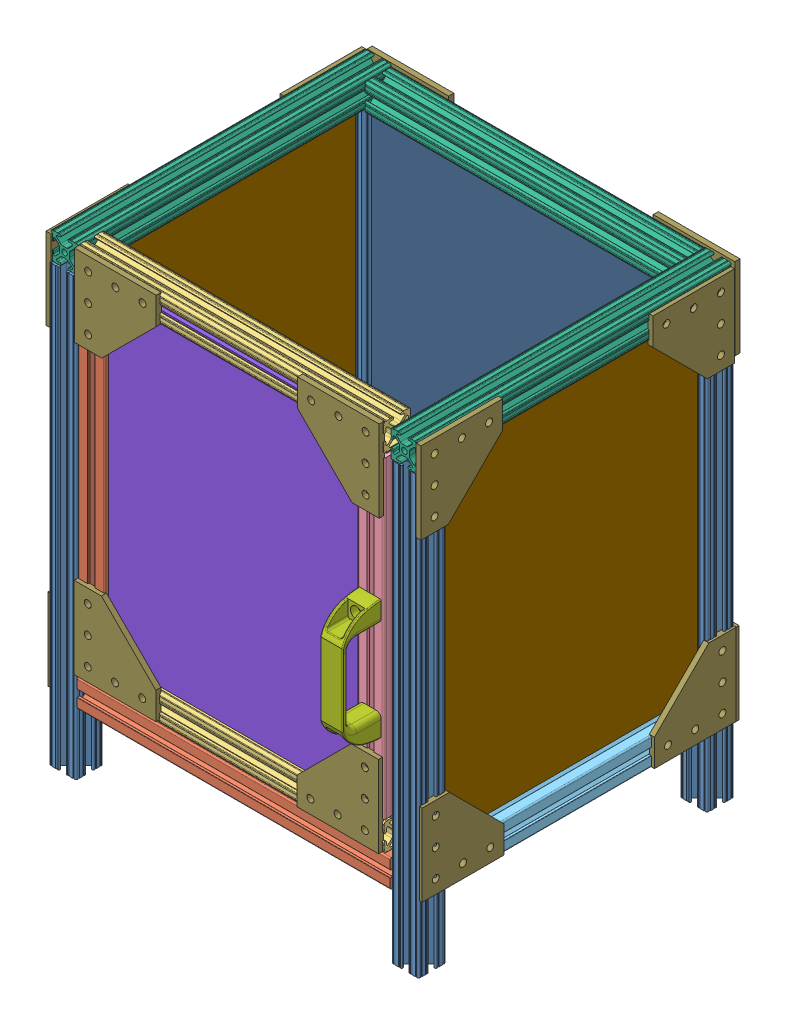
SolidWorks assembly Box_Ext_6_25_2024, configuration Default. Lengths in mm.
Overall size (350.11 433.76 336.93).
41 component instances, 12 part files, 0 mates.
Components (placement in the parent):
- 1A_1D_16in47065T801_T-Slotted Framing rail-1: 1A_1D_16in47065T801_T-Slotted Framing rail [47065T801] at (-239.4342 265.817 193.973) x (0 0 1) z (0 1 0) size (25.4 25.4 406.4)
- 1A_1D_16in47065T801_T-Slotted Framing rail-2: 1A_1D_16in47065T801_T-Slotted Framing rail [47065T801] at (-240.0711 265.9257 462.8579) x (1 0 0) z (0 -1 0) size (25.4 25.4 406.4)
- 1A_1D_16in47065T801_T-Slotted Framing rail-3: 1A_1D_16in47065T801_T-Slotted Framing rail [47065T801] at (79.5241 264.9055 193.6515) x (1 0 0) z (0 -1 0) size (25.4 25.4 406.4)
- 1A_1D_16in47065T801_T-Slotted Framing rail-4: 1A_1D_16in47065T801_T-Slotted Framing rail [47065T801] at (79.0395 264.9055 462.2875) x (1 0 0) z (0 -1 0) size (25.4 25.4 406.4)
- 3A_3B_3C_11_5in6575N217_T-Slotted Framing Rail-1: 3A_3B_3C_11_5in6575N217_T-Slotted Framing Rail [6575N217] at (-80.5158 133.3354 462.6399) x (0 0 1) z (1 0 0) size (25.4 25.4 292.1)
- 5A_5B_11_25in_47065T846_T-Slotted Framing-1: 5A_5B_11_25in_47065T846_T-Slotted Framing [47065T846] at (-83.0751 159.6001 462.6399) x (0 0 1) z (-1 0 0) size (25.4 25.4 285.75)
- 3A_3B_3C_11_5in6575N217_T-Slotted Framing Rail-2: 3A_3B_3C_11_5in6575N217_T-Slotted Framing Rail [6575N217] at (-213.4294 321.0324 462.7499) x (1 0 0) z (0 -1 0) size (25.4 25.4 292.1)
- 6_11_5in6575N218_T-Slotted Framing Rail-1: 6_11_5in6575N218_T-Slotted Framing Rail [6575N218] at (46.9584 319.918 462.4695) x (0 1 0) z (1 0 0) size (292.1 25.4 25.4)
- 5A_5B_11_25in_47065T846_T-Slotted Framing-2: 5A_5B_11_25in_47065T846_T-Slotted Framing [47065T846] at (-83.4418 482.5282 462.8007) x (0 1 0) z (1 0 0) size (25.4 25.4 285.75)
- 2A_2B_9_5in6575N217_T-Slotted Framing Rail-1: 2A_2B_9_5in6575N217_T-Slotted Framing Rail [6575N217] at (78.5396 136.1503 326.476) size (25.4 25.4 241.3)
- 2A_2B_9_5in6575N217_T-Slotted Framing Rail-2: 2A_2B_9_5in6575N217_T-Slotted Framing Rail [6575N217] at (-239.3609 136.2243 327.8144) x (0 1 0) z (0 0 1) size (25.4 25.4 241.3)
- 3A_3B_3C_11_5in6575N217_T-Slotted Framing Rail-3: 3A_3B_3C_11_5in6575N217_T-Slotted Framing Rail [6575N217] at (-81.1923 133.366 194.3443) x (0 0.008727 0.999962) z (-1 0 0) size (25.4 25.4 292.1)
- 4A_4C_11_5in47065T801_T-Slotted Framing rail-1: 4A_4C_11_5in47065T801_T-Slotted Framing rail [47065T801] at (-240.0375 481.9511 327.6131) size (25.4 25.4 292.1)
- 4A_4C_11_5in47065T801_T-Slotted Framing rail-2: 4A_4C_11_5in47065T801_T-Slotted Framing rail [47065T801] at (77.9867 481.0907 328.468) size (25.4 25.4 292.1)
- 4A_4C_11_5in47065T801_T-Slotted Framing rail-3: 4A_4C_11_5in47065T801_T-Slotted Framing rail [47065T801] at (-80.1705 480.6089 194.2481) x (0 1 0) z (1 0 0) size (25.4 25.4 292.1)
- 47065T595_Red Plastic Pull Handle-1: 47065T595_Red Plastic Pull Handle [47065T595] at (47.7995 342.8306 476.5075) x (-1 0 0) z (0 0 1) size (21.11 112.11 36)
- pD-1: pD [Default] at (39.7962 478.6241 471.804) x (-1 0 0) z (0 -1 0) size (250.83 4.76 304.8)
- pA-1: pA [Default] at (80.357 151.2499 200.6755) x (0 1 0) z (0 0 1) size (317.5 4.76 254)
- pA-2: pA [Default] at (-240.7265 149.3164 198.8892) x (0 1 0) z (0 0 1) size (317.5 4.76 254)
- pB-3: pB [Default] at (-237.6602 138.9797 195.7037) x (0 1 0) z (1 0 0) size (330.2 4.76 304.8)
- pE-1: pE [Default] at (-227.8794 132.6636 204.9097) size (50.8 4.76 254)
- pE-2: pE [Default] at (-164.9525 130.5241 208.5576) size (50.8 4.76 254)
- pE-3: pE [Default] at (-102.4815 131.3886 208.1017) size (50.8 4.76 254)
- pE-4: pE [Default] at (-41.8346 135.1169 204.9097) size (50.8 4.76 254)
- pE-5: pE [Default] at (16.0764 135.6961 203.9977) size (50.8 4.76 254)
- 47065T267_T-Slotted Framing-1: 47065T267_T-Slotted Framing [47065T267] at (-253.577 491.9605 474.9883) x (0 -1 0) z (1 0 0) size (76.2 76.2 4.76)
- 47065T267_T-Slotted Framing-2: 47065T267_T-Slotted Framing [47065T267] at (-253.577 124.4406 180.3869) x (0 1 0) z (1 0 0) size (76.2 76.2 4.76)
- 47065T267_T-Slotted Framing-3: 47065T267_T-Slotted Framing [47065T267] at (-253.577 123.3787 473.2185) x (0 0 -1) z (1 0 0) size (76.2 76.2 4.76)
- 47065T267_T-Slotted Framing-4: 47065T267_T-Slotted Framing [47065T267] at (-253.577 493.7304 180.3869) x (0 0 1) z (1 0 0) size (76.2 76.2 4.76)
- 47065T267_T-Slotted Framing-5: 47065T267_T-Slotted Framing [47065T267] at (-225.7817 150.6545 476.5665) size (76.2 76.2 4.76)
- 47065T267_T-Slotted Framing-6: 47065T267_T-Slotted Framing [47065T267] at (-225.4278 495.4606 476.5665) x (1 0 0) z (0 0 -1) size (76.2 76.2 4.76)
- 47065T267_T-Slotted Framing-7: 47065T267_T-Slotted Framing [47065T267] at (58.1546 147.8233 476.5665) x (-1 0 0) z (0 0 -1) size (76.2 76.2 4.76)
- 47065T267_T-Slotted Framing-8: 47065T267_T-Slotted Framing [47065T267] at (58.8624 495.4606 476.5665) x (0 -1 0) z (0 0 -1) size (76.2 76.2 4.76)
- 47065T267_T-Slotted Framing-9: 47065T267_T-Slotted Framing [47065T267] at (91.7738 123.8122 181.2308) x (0 1 0) z (1 0 0) size (76.2 76.2 4.76)
- 47065T267_T-Slotted Framing-10: 47065T267_T-Slotted Framing [47065T267] at (91.7738 124.1663 474.1306) x (0 0 -1) z (1 0 0) size (76.2 76.2 4.76)
- 47065T267_T-Slotted Framing-11: 47065T267_T-Slotted Framing [47065T267] at (91.7738 490.3616 182.6471) x (0 0 1) z (1 0 0) size (76.2 76.2 4.76)
- 47065T267_T-Slotted Framing-12: 47065T267_T-Slotted Framing [47065T267] at (91.7738 493.5483 475.1928) x (0 -1 0) z (1 0 0) size (76.2 76.2 4.76)
- 47065T267_T-Slotted Framing-13: 47065T267_T-Slotted Framing [47065T267] at (-252.1374 121.6877 177.9621) size (76.2 76.2 4.76)
- 47065T267_T-Slotted Framing-14: 47065T267_T-Slotted Framing [47065T267] at (91.3964 120.9795 177.9621) x (-1 0 0) z (0 0 -1) size (76.2 76.2 4.76)
- 47065T267_T-Slotted Framing-15: 47065T267_T-Slotted Framing [47065T267] at (-251.0752 494.2565 177.9621) x (1 0 0) z (0 0 -1) size (76.2 76.2 4.76)
- 47065T267_T-Slotted Framing-16: 47065T267_T-Slotted Framing [47065T267] at (92.1046 493.9024 177.9621) x (-1 0 0) z (0 0 1) size (76.2 76.2 4.76)
